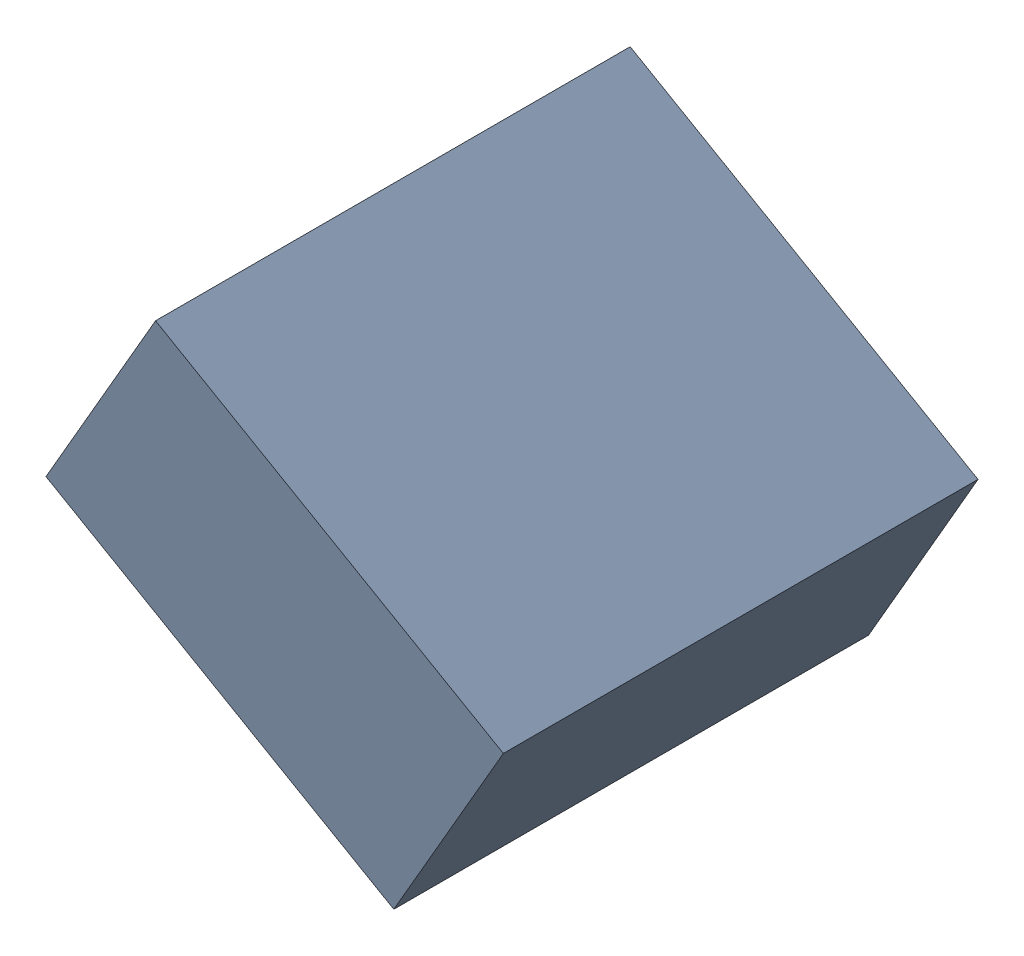
SolidWorks assembly C25_TDA6, configuration Standard. Lengths in mm.
Overall size (1.25 1.07 1.3).
2 component instances, 1 part files, 0 mates.
Components (placement in the parent):
- 885543056-1: 885543056 [Standard] at (-34.2808 24.8163 0) size (1.25 1.07 1.3)
  - Extruded_23-1: Extruded_23 [Standard] at origin size (1.25 1.07 1.3)
